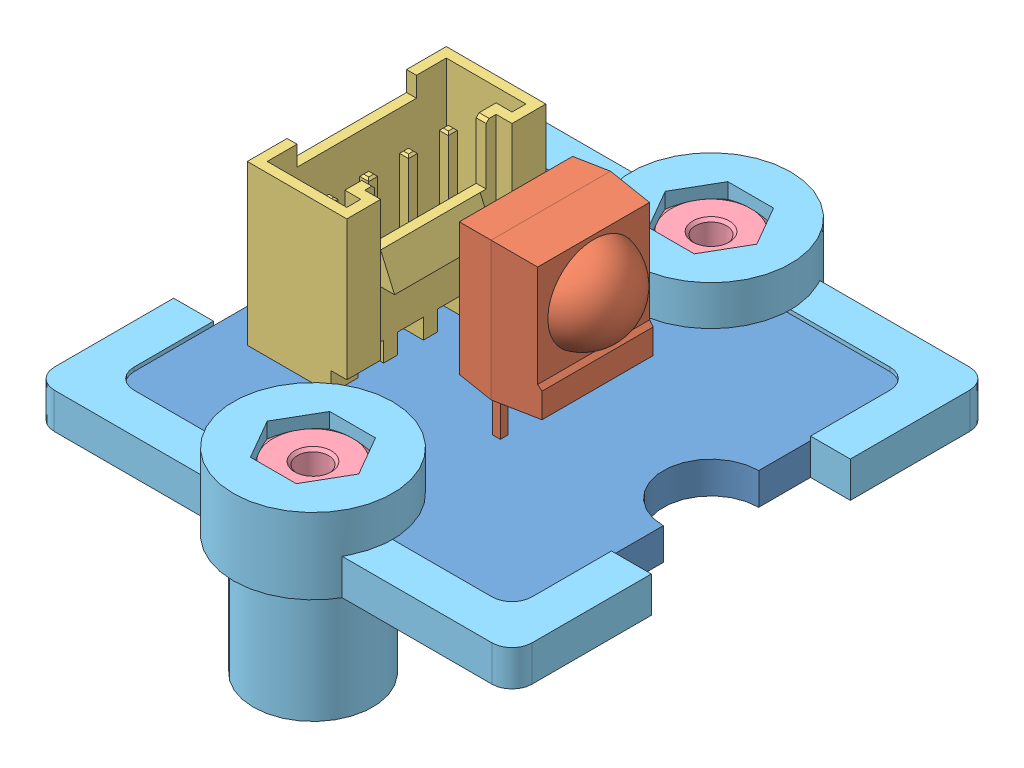
SolidWorks assembly ir_recep, configuration Défaut. Lengths in mm.
Overall size (24 16.3 28).
8 component instances, 5 part files, 12 mates.
Components (placement in the parent):
- Grove IR recepteur-1: Grove IR recepteur [Défaut] at (4.4508 -3.7677 0) size (20 11.7 23.6)
  - PCB grove 20x20-1: PCB grove 20x20 [Défaut] at (-0.787 -0.8532 23.6) size (20 1.6 23.6)
  - Recepteur-1: Recepteur [Défaut] at (1.163 6.7468 23.6) x (0 0 -1) z (1 0 0) size (6 10.7 5.7)
  - Connecteur Grove (droit)-1: Connecteur Grove (droit) [Défaut] at (-4.087 0.7468 23.6) x (0 0 -1) z (1 0 0) size (10 11 5)
- ecrou-h-1: ecrou-h [6007 HU M2] at (3.6638 -1.4209 33.6) x (0 0 -1) z (1 0 0) size (4 1.6 4.62)
- ecrou-h-2: ecrou-h [6007 HU M2] at (3.6638 -1.4209 13.6) x (0 0 1) z (-1 0 0) size (4 1.6 4.62)
- capuchon-grove-1: capuchon-grove [Défaut] at (3.6638 -2.8209 28.6) x (-1 0 0) z (0 0 1) size (24 9.8 9)
- capuchon-grove-2: capuchon-grove [Défaut] at (3.6638 -2.8209 18.6) x (1 0 0) z (0 0 -1) size (24 9.8 9)
Mates (geometry in assembly coordinates):
- Coïncidente1: coincident anti-aligned: plane of Grove IR recepteur-1/PCB grove 20x20-1 through (3.6638 -3.0209 13.6) normal (0 0 -1); plane of capuchon-grove-2 through (5.6638 -4.6209 13.6) normal (0 0 1)
- Coïncidente2: coincident anti-aligned: plane of Grove IR recepteur-1/PCB grove 20x20-1 through (-6.3362 -3.0209 23.6) normal (-1 0 0); plane of capuchon-grove-2 through (-6.3362 -4.6209 18.6) normal (1 0 0)
- Coaxiale1: concentric anti-aligned: cylinder of Grove IR recepteur-1/PCB grove 20x20-1 through (3.6638 -3.0209 13.6) axis (0 -1 0) radius 1.1; cylinder of ecrou-h-2 through (3.6638 -3.0209 13.6) axis (0 1 0) radius 0.7835
- Parallèle1: parallel anti-aligned: plane of ecrou-h-2 through (4.8185 -3.0209 11.6) normal (0 0 -1); plane of capuchon-grove-2 through (4.8138 -11.8209 11.6081) normal (0 0 1)
- Coïncidente5: coincident anti-aligned: plane of Grove IR recepteur-1/PCB grove 20x20-1 through (3.6638 -3.0209 23.6) normal (0 1 0); plane of ecrou-h-2 through (4.8185 -3.0209 15.6) normal (0 -1 0)
- Coïncidente6: coincident anti-aligned: plane of Grove IR recepteur-1/PCB grove 20x20-1 through (13.6638 -3.0209 23.6) normal (1 0 0); plane of capuchon-grove-1 through (13.6638 -4.6209 28.6) normal (-1 0 0)
- Coïncidente7: coincident anti-aligned: plane of Grove IR recepteur-1/PCB grove 20x20-1 through (3.6638 -3.0209 33.6) normal (0 0 1); plane of capuchon-grove-1 through (1.6638 -4.6209 33.6) normal (0 0 -1)
- Coaxiale2: concentric anti-aligned: cylinder of Grove IR recepteur-1/PCB grove 20x20-1 through (3.6638 -3.0209 33.6) axis (0 -1 0) radius 1.1; cylinder of ecrou-h-1 through (3.6638 -3.0209 33.6) axis (0 1 0) radius 0.7835
- Parallèle2: parallel anti-aligned: plane of ecrou-h-1 through (4.8185 -3.0209 31.6) normal (0 0 -1); plane of capuchon-grove-1 through (4.8138 -11.8209 31.6081) normal (0 0 1)
- Coïncidente10: coincident anti-aligned: plane of Grove IR recepteur-1/PCB grove 20x20-1 through (3.6638 -3.0209 23.6) normal (0 1 0); plane of ecrou-h-1 through (2.5091 -3.0209 31.6) normal (0 -1 0)
- Coïncidente11: coincident anti-aligned: plane of Grove IR recepteur-1/PCB grove 20x20-1 through (3.6638 -4.6209 23.6) normal (0 -1 0); plane of capuchon-grove-1 through (3.6638 -4.6209 33.6) normal (0 1 0)
- Coïncidente12: coincident anti-aligned: plane of Grove IR recepteur-1/PCB grove 20x20-1 through (3.6638 -4.6209 23.6) normal (0 -1 0); plane of capuchon-grove-2 through (3.6638 -4.6209 13.6) normal (0 1 0)
